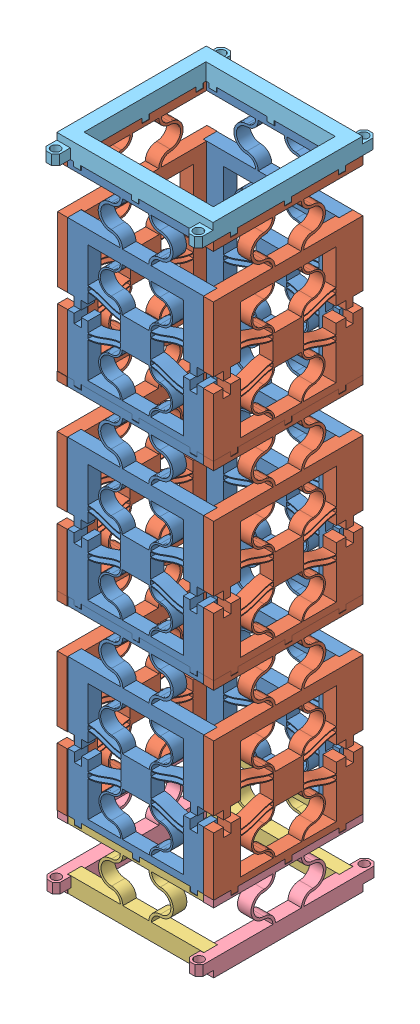
SolidWorks assembly Assem1, configuration Default. Lengths in mm.
Overall size (46.4 194.41 53.3).
17 component instances, 5 part files, 56 mates.
Components (placement in the parent):
- MM_ver1_of_ROC_ver8_FB-1: MM_ver1_of_ROC_ver8_FB [Default] at (-11.2895 123.3553 39.4876) size (44.3 57.77 4)
- MM_ver1_of_ROC_ver8_LR-1: MM_ver1_of_ROC_ver8_LR [Default] at (18.1105 123.3553 55.3876) x (0 0 1) z (-1 0 0) size (44.4 57.77 4)
- MM_ver1_of_ROC_ver8_FB-2: MM_ver1_of_ROC_ver8_FB [Default] at (-11.2895 179.8257 39.4876) size (44.3 57.77 4)
- MM_ver1_of_ROC_ver8_LR-2: MM_ver1_of_ROC_ver8_LR [Default] at (18.1105 179.8257 55.3876) x (0 0 1) z (-1 0 0) size (44.4 57.77 4)
- MM_FB_nastavek-1: MM_FB_nastavek [Default] at (-11.2895 123.3553 39.4876) size (44.3 20 4)
- MM_LR_nastavek-1: MM_LR_nastavek [Default] at (18.1105 123.3553 55.3876) x (0 0 1) z (-1 0 0) size (53.1 20 4)
- MM_ver1_of_ROC_ver8_FB-3: MM_ver1_of_ROC_ver8_FB [Default] at (1.1105 179.8257 83.7876) x (-1 0 0) z (0 0 -1) size (44.3 57.77 4)
- MM_ver1_of_ROC_ver8_FB-4: MM_ver1_of_ROC_ver8_FB [Default] at (1.1105 123.3553 83.6876) x (-1 0 0) z (0 0 -1) size (44.3 57.77 4)
- MM_LR_nastavek-2: MM_LR_nastavek [Default] at (-28.2895 123.3553 67.7876) x (0 0 -1) z (1 0 0) size (53.1 20 4)
- MM_FB_nastavek-2: MM_FB_nastavek [Default] at (1.1105 123.3553 83.6876) x (-1 0 0) z (0 0 -1) size (44.3 20 4)
- MM_ver1_of_ROC_ver8_LR-3: MM_ver1_of_ROC_ver8_LR [Default] at (-28.2895 179.8257 67.8876) x (0 0 -1) z (1 0 0) size (44.4 57.77 4)
- MM_ver1_of_ROC_ver8_LR-4: MM_ver1_of_ROC_ver8_LR [Default] at (-28.2895 123.3553 67.8876) x (0 0 -1) z (1 0 0) size (44.4 57.77 4)
- MM_ver1_of_ROC_ver8_FB-5: MM_ver1_of_ROC_ver8_FB [Default] at (1.1105 236.2961 83.7876) x (-1 0 0) z (0 0 -1) size (44.3 57.77 4)
- MM_ver1_of_ROC_ver8_FB-6: MM_ver1_of_ROC_ver8_FB [Default] at (-11.2895 236.2961 39.4876) size (44.3 57.77 4)
- MM_ver1_of_ROC_ver8_LR-5: MM_ver1_of_ROC_ver8_LR [Default] at (-28.2895 236.2961 67.7876) x (0 0 -1) z (1 0 0) size (44.4 57.77 4)
- MM_ver1_of_ROC_ver8_LR-6: MM_ver1_of_ROC_ver8_LR [Default] at (18.1105 236.2961 55.4876) x (0 0 1) z (-1 0 0) size (44.4 57.77 4)
- MM_zgornji_nastavek-2: MM_zgornji_nastavek [Default] at (18.1105 238.7961 55.5876) x (0 0 1) z (-1 0 0) size (53.1 6.3 46.4)
Mates (geometry in assembly coordinates):
- Coincident1: coincident aligned: plane of MM_ver1_of_ROC_ver8_FB-1 through (-11.2895 50.3849 43.4876) normal (0 1 0); plane of MM_ver1_of_ROC_ver8_LR-1 through (14.1105 50.3849 55.3876) normal (0 1 0)
- Coincident2: coincident anti-aligned: plane of MM_ver1_of_ROC_ver8_FB-1 through (15.1105 46.3849 43.4876) normal (1 0 0); plane of MM_ver1_of_ROC_ver8_LR-1 through (15.1105 11.4144 55.3876) normal (-1 0 0)
- Coincident3: coincident anti-aligned: plane of MM_ver1_of_ROC_ver8_FB-1 through (-11.2895 11.4144 43.4876) normal (0 0 1); plane of MM_ver1_of_ROC_ver8_LR-1 through (15.1105 50.3849 43.4876) normal (0 0 -1)
- Coincident4: coincident aligned: plane of MM_ver1_of_ROC_ver8_FB-1 through (-11.2895 11.4144 39.4876) normal (0 0 -1); plane of MM_ver1_of_ROC_ver8_FB-2 through (-11.2895 67.8849 39.4876) normal (0 0 -1)
- Coincident5: coincident anti-aligned: plane of MM_ver1_of_ROC_ver8_FB-1 through (20.6021 65.8849 49.4876) normal (0 1 0); plane of MM_ver1_of_ROC_ver8_FB-2 through (23.1966 65.8849 49.4876) normal (0 -1 0)
- Width1: width anti-aligned: plane of MM_ver1_of_ROC_ver8_FB-2 through (-4.0295 65.8849 45.9745) normal (1 0 0); plane of MM_ver1_of_ROC_ver8_FB-1 through (-6.1495 65.8849 45.9745) normal (-1 0 0); plane of MM_ver1_of_ROC_ver8_FB-2 through (-4.0145 65.8849 43.4876) normal (-1 0 0); plane of MM_ver1_of_ROC_ver8_FB-1 through (-6.1645 65.8849 43.4876) normal (1 0 0)
- Coincident6: coincident aligned: plane of MM_ver1_of_ROC_ver8_LR-1 through (18.1105 74.2944 55.3876) normal (1 0 0); plane of MM_ver1_of_ROC_ver8_LR-2 through (18.1105 130.7648 55.3876) normal (1 0 0)
- Coincident7: coincident anti-aligned: plane of MM_ver1_of_ROC_ver8_LR-1 through (18.1105 65.8849 31.5604) normal (0 1 0); plane of MM_ver1_of_ROC_ver8_LR-2 through (18.1105 65.8849 29.0928) normal (0 -1 0)
- Width2: width aligned: plane of MM_ver1_of_ROC_ver8_LR-1 through (18.1105 65.8849 62.6626) normal (0 0 -1); plane of MM_ver1_of_ROC_ver8_LR-2 through (18.1105 65.8849 60.5126) normal (0 0 1); plane of MM_ver1_of_ROC_ver8_LR-1 through (20.5974 65.8849 60.5276) normal (0 0 -1); plane of MM_ver1_of_ROC_ver8_LR-2 through (20.5974 65.8849 62.6476) normal (0 0 1)
- Coincident8: coincident aligned: plane of MM_ver1_of_ROC_ver8_FB-2 through (-11.2895 67.8849 39.4876) normal (0 0 -1); plane of MM_FB_nastavek-1 through (-11.2895 11.4144 39.4876) normal (0 0 -1)
- Coincident11: coincident aligned: plane of MM_ver1_of_ROC_ver8_LR-2 through (18.1105 130.7648 55.3876) normal (1 0 0); plane of MM_LR_nastavek-1 through (18.1105 133.2648 55.4876) normal (1 0 0)
- Coincident12: coincident anti-aligned: plane of MM_ver1_of_ROC_ver8_LR-2 through (18.1105 122.3553 31.5604) normal (0 1 0); plane of MM_LR_nastavek-1 through (18.1105 122.3553 35.1376) normal (0 -1 0)
- Coincident13: coincident aligned: plane of MM_ver1_of_ROC_ver8_FB-2 through (-11.2895 67.8849 39.4876) normal (0 0 -1); plane of MM_LR_nastavek-1 through (62.7912 70.3849 39.4876) normal (0 0 -1)
- Coincident14: coincident aligned: plane of MM_ver1_of_ROC_ver8_FB-1 through (-11.2895 11.4144 39.4876) normal (0 0 -1); plane of MM_FB_nastavek-1 through (-11.2895 11.4144 39.4876) normal (0 0 -1)
- Coincident15: coincident anti-aligned: plane of MM_ver1_of_ROC_ver8_FB-1 through (23.1966 9.4144 49.4876) normal (0 -1 0); plane of MM_FB_nastavek-1 through (24.9312 9.4144 49.4876) normal (0 1 0)
- Coincident16: coincident aligned: plane of MM_ver1_of_ROC_ver8_FB-1 through (-25.2895 11.4144 43.4876) normal (-1 0 0); plane of MM_FB_nastavek-1 through (-25.2895 11.4144 43.4876) normal (-1 0 0)
- Coincident17: coincident aligned: plane of MM_ver1_of_ROC_ver8_LR-1 through (18.1105 74.2944 55.3876) normal (1 0 0); plane of MM_LR_nastavek-1 through (18.1105 74.2944 55.3876) normal (1 0 0)
- Coincident18: coincident anti-aligned: plane of MM_ver1_of_ROC_ver8_LR-1 through (18.1105 9.4144 29.0928) normal (0 -1 0); plane of MM_LR_nastavek-1 through (24.1105 9.4144 24.3793) normal (0 1 0)
- Coincident19: coincident aligned: plane of MM_ver1_of_ROC_ver8_LR-1 through (14.1105 11.4144 39.3876) normal (0 0 -1); plane of MM_LR_nastavek-1 through (14.1105 11.4144 39.3876) normal (0 0 -1)
- Coincident25: coincident anti-aligned: plane of MM_FB_nastavek-1 through (-25.2895 -5.5856 -1.2206) normal (-1 0 0); plane of MM_LR_nastavek-2 through (-25.2895 180.3257 43.4876) normal (1 0 0)
- Coincident26: coincident anti-aligned: plane of MM_FB_nastavek-1 through (-11.2895 11.4144 43.4876) normal (0 0 1); plane of MM_LR_nastavek-2 through (-25.2895 180.3257 43.4876) normal (0 0 -1)
- Coincident27: coincident aligned: plane of MM_FB_nastavek-1 through (-25.2895 -5.5856 -1.2206) normal (0 1 0); plane of MM_LR_nastavek-2 through (-28.2895 -5.5856 88.1376) normal (0 1 0)
- Coincident28: coincident aligned: plane of MM_LR_nastavek-2 through (-28.2895 -5.5856 88.1376) normal (0 1 0); plane of MM_FB_nastavek-2 through (15.1105 -5.5856 124.3959) normal (0 1 0)
- Coincident29: coincident anti-aligned: plane of MM_LR_nastavek-2 through (-25.2895 180.3257 79.6876) normal (0 0 1); plane of MM_FB_nastavek-2 through (1.1105 11.4144 79.6876) normal (0 0 -1)
- Coincident30: coincident anti-aligned: plane of MM_LR_nastavek-2 through (-25.2895 180.3257 79.6876) normal (1 0 0); plane of MM_FB_nastavek-2 through (-25.2895 -5.5856 124.3959) normal (-1 0 0)
- Coincident31: coincident anti-aligned: plane of MM_zgornji_nastavek-1 through (18.1105 122.3553 35.1376) normal (0 -1 0); plane of MM_ver1_of_ROC_ver8_LR-3 through (-28.2895 122.3553 91.7149) normal (0 1 0)
- Coincident32: coincident aligned: plane of MM_zgornji_nastavek-1 through (-28.2895 133.2648 55.4876) normal (-1 0 0); plane of MM_ver1_of_ROC_ver8_LR-3 through (-28.2895 130.7648 67.8876) normal (-1 0 0)
- Coincident34: coincident anti-aligned: plane of MM_ver1_of_ROC_ver8_LR-3 through (-28.2895 65.8849 94.1825) normal (0 -1 0); plane of MM_ver1_of_ROC_ver8_LR-4 through (-28.2895 65.8849 91.7149) normal (0 1 0)
- Coincident35: coincident aligned: plane of MM_ver1_of_ROC_ver8_LR-3 through (-28.2895 130.7648 67.8876) normal (-1 0 0); plane of MM_ver1_of_ROC_ver8_LR-4 through (-28.2895 74.2944 67.8876) normal (-1 0 0)
- Coincident36: coincident aligned: plane of MM_ver1_of_ROC_ver8_LR-3 through (-24.2895 67.8849 39.4876) normal (0 0 -1); plane of MM_ver1_of_ROC_ver8_LR-4 through (-28.2895 60.447 39.4876) normal (0 0 -1)
- Coincident37: coincident anti-aligned: plane of MM_ver1_of_ROC_ver8_FB-3 through (1.1105 67.8849 79.7876) normal (0 0 -1); plane of MM_ver1_of_ROC_ver8_LR-3 through (-25.2895 106.8553 79.7876) normal (0 0 1)
- Coincident38: coincident: plane of MM_zgornji_nastavek-1 through (62.7912 70.3849 83.8876) normal (0 0 1); plane of MM_ver1_of_ROC_ver8_FB-3 through (1.1105 67.8849 83.7876) normal (0 0 1)
- Coincident39: coincident: plane of MM_zgornji_nastavek-1 through (18.1105 122.3553 35.1376) normal (0 -1 0); plane of MM_ver1_of_ROC_ver8_FB-3 through (-30.781 122.3553 73.7876) normal (0 1 0)
- Coincident40: coincident anti-aligned: plane of MM_ver1_of_ROC_ver8_LR-2 through (15.1105 67.8849 55.3876) normal (-1 0 0); plane of MM_ver1_of_ROC_ver8_FB-3 through (15.1105 102.8553 79.7876) normal (1 0 0)
- Coincident41: coincident anti-aligned: plane of MM_ver1_of_ROC_ver8_LR-1 through (15.1105 50.3849 79.6876) normal (0 0 1); plane of MM_ver1_of_ROC_ver8_FB-4 through (1.1105 11.4144 79.6876) normal (0 0 -1)
- Coincident42: coincident anti-aligned: plane of MM_ver1_of_ROC_ver8_FB-3 through (-33.3755 65.8849 73.7876) normal (0 -1 0); plane of MM_ver1_of_ROC_ver8_FB-4 through (-30.781 65.8849 73.6876) normal (0 1 0)
- Coincident43: coincident anti-aligned: plane of MM_ver1_of_ROC_ver8_LR-1 through (15.1105 11.4144 55.3876) normal (-1 0 0); plane of MM_ver1_of_ROC_ver8_FB-4 through (15.1105 46.3849 79.6876) normal (1 0 0)
- Coincident44: coincident aligned: plane of MM_ver1_of_ROC_ver8_FB-2 through (-11.2895 67.8849 39.4876) normal (0 0 -1); plane of MM_ver1_of_ROC_ver8_LR-3 through (-24.2895 102.8553 39.4876) normal (0 0 -1)
- Coincident45: coincident aligned: plane of MM_ver1_of_ROC_ver8_FB-2 through (-11.2895 106.8553 43.4876) normal (0 1 0); plane of MM_ver1_of_ROC_ver8_LR-3 through (-24.2895 106.8553 67.8876) normal (0 1 0)
- Coincident46: coincident anti-aligned: plane of MM_ver1_of_ROC_ver8_FB-2 through (-25.2895 102.8553 43.4876) normal (-1 0 0); plane of MM_ver1_of_ROC_ver8_LR-3 through (-25.2895 67.8849 67.8876) normal (1 0 0)
- Coincident47: coincident aligned: plane of MM_ver1_of_ROC_ver8_LR-2 through (18.1105 122.3553 31.5604) normal (0 1 0); plane of MM_ver1_of_ROC_ver8_FB-3 through (-30.781 122.3553 73.7876) normal (0 1 0)
- Coincident48: coincident aligned: plane of MM_ver1_of_ROC_ver8_FB-3 through (1.1105 67.8849 83.7876) normal (0 0 1); plane of MM_ver1_of_ROC_ver8_FB-5 through (1.1105 124.3553 83.7876) normal (0 0 1)
- Coincident49: coincident anti-aligned: plane of MM_ver1_of_ROC_ver8_FB-3 through (-30.781 122.3553 73.7876) normal (0 1 0); plane of MM_ver1_of_ROC_ver8_FB-5 through (-33.3755 122.3553 73.7876) normal (0 -1 0)
- Coincident50: coincident aligned: plane of MM_ver1_of_ROC_ver8_FB-3 through (-25.2895 102.8553 79.7876) normal (-1 0 0); plane of MM_ver1_of_ROC_ver8_FB-5 through (-25.2895 124.3553 79.7876) normal (-1 0 0)
- Coincident51: coincident aligned: plane of MM_ver1_of_ROC_ver8_FB-2 through (-11.2895 67.8849 39.4876) normal (0 0 -1); plane of MM_ver1_of_ROC_ver8_FB-6 through (-11.2895 124.3553 39.4876) normal (0 0 -1)
- Coincident52: coincident anti-aligned: plane of MM_ver1_of_ROC_ver8_FB-2 through (20.6021 122.3553 49.4876) normal (0 1 0); plane of MM_ver1_of_ROC_ver8_FB-6 through (23.1966 122.3553 49.4876) normal (0 -1 0)
- Coincident53: coincident anti-aligned: plane of MM_ver1_of_ROC_ver8_LR-3 through (-25.2895 67.8849 67.8876) normal (1 0 0); plane of MM_ver1_of_ROC_ver8_FB-6 through (-25.2895 124.3553 43.4876) normal (-1 0 0)
- Coincident54: coincident aligned: plane of MM_ver1_of_ROC_ver8_LR-3 through (-28.2895 130.7648 67.8876) normal (-1 0 0); plane of MM_ver1_of_ROC_ver8_LR-5 through (-28.2895 187.2352 67.7876) normal (-1 0 0)
- Coincident55: coincident anti-aligned: plane of MM_ver1_of_ROC_ver8_LR-3 through (-28.2895 122.3553 91.7149) normal (0 1 0); plane of MM_ver1_of_ROC_ver8_LR-5 through (-28.2895 122.3553 94.0825) normal (0 -1 0)
- Coincident56: coincident aligned: plane of MM_ver1_of_ROC_ver8_FB-5 through (1.1105 124.3553 83.7876) normal (0 0 1); plane of MM_ver1_of_ROC_ver8_LR-5 through (-24.2895 124.3553 83.7876) normal (0 0 1)
- Coincident57: coincident aligned: plane of MM_ver1_of_ROC_ver8_LR-2 through (18.1105 130.7648 55.3876) normal (1 0 0); plane of MM_ver1_of_ROC_ver8_LR-6 through (18.1105 187.2352 55.4876) normal (1 0 0)
- Coincident58: coincident anti-aligned: plane of MM_ver1_of_ROC_ver8_LR-2 through (18.1105 122.3553 31.5604) normal (0 1 0); plane of MM_ver1_of_ROC_ver8_LR-6 through (18.1105 122.3553 29.1928) normal (0 -1 0)
- Coincident59: coincident aligned: plane of MM_ver1_of_ROC_ver8_FB-6 through (-11.2895 124.3553 39.4876) normal (0 0 -1); plane of MM_ver1_of_ROC_ver8_LR-6 through (14.1105 124.3553 39.4876) normal (0 0 -1)
- Coincident60: coincident anti-aligned: plane of MM_ver1_of_ROC_ver8_FB-6 through (20.6021 178.8257 49.4876) normal (0 1 0); plane of MM_zgornji_nastavek-2 through (18.1105 178.8257 35.2376) normal (0 -1 0)
- Coincident61: coincident aligned: plane of MM_ver1_of_ROC_ver8_LR-6 through (18.1105 187.2352 55.4876) normal (1 0 0); plane of MM_zgornji_nastavek-2 through (18.1105 189.7352 55.5876) normal (1 0 0)
- Width4: width anti-aligned: plane of MM_zgornji_nastavek-2 through (-30.7763 178.8257 60.6276) normal (0 0 -1); plane of MM_ver1_of_ROC_ver8_LR-6 through (-30.7763 178.8257 62.7476) normal (0 0 1); plane of MM_zgornji_nastavek-2 through (18.1105 178.8257 60.6126) normal (0 0 1); plane of MM_ver1_of_ROC_ver8_LR-6 through (18.1105 178.8257 62.7626) normal (0 0 -1)
